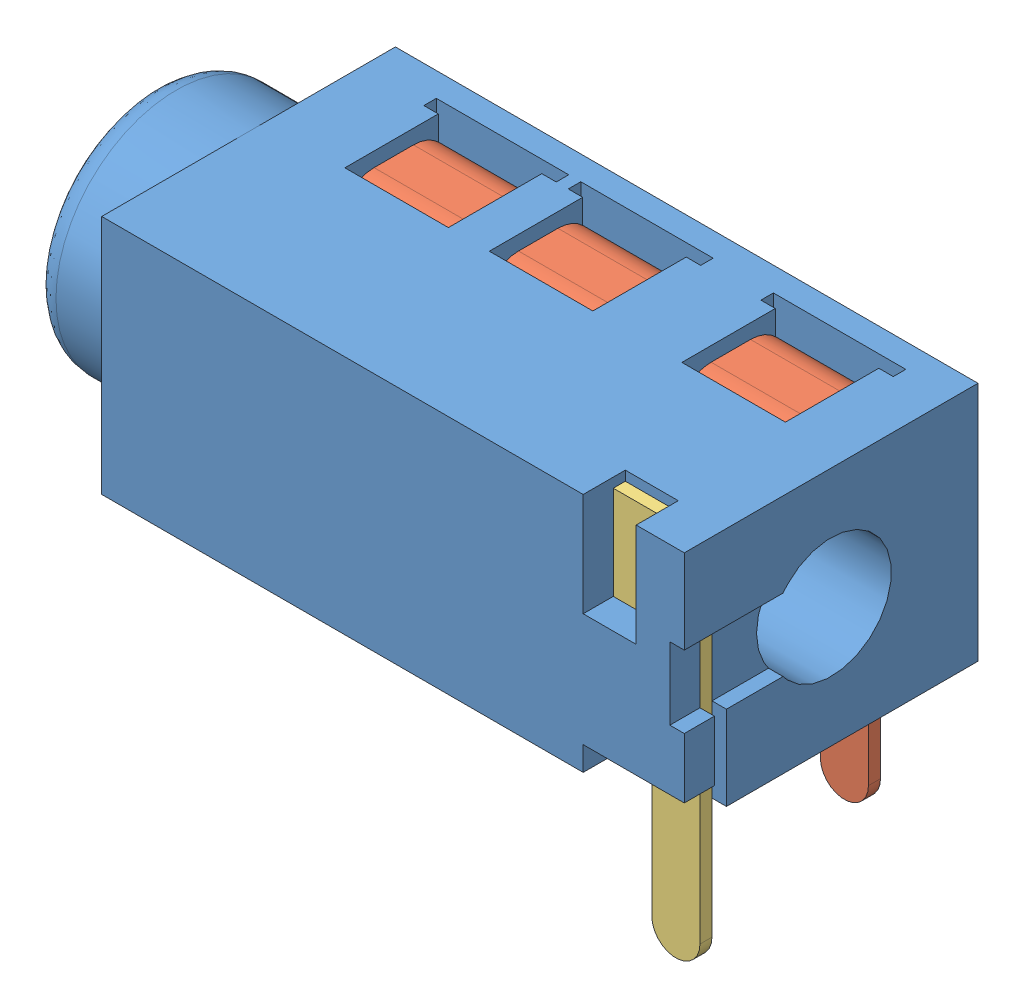
SolidWorks assembly PJ320A, configuration 默认. Lengths in mm.
Overall size (14.1 8 6.1).
5 component instances, 3 part files, 10 mates.
Components (placement in the parent):
- PJ320A胶壳-1: PJ320A胶壳 [默认] at (2.4399 13.6973 7.311) size (14.1 6 6.1)
- PJ320A-Pin-A-1: PJ320A-Pin-A [默认] at (6.1399 11.6833 5.136) x (0 1 0) z (0 0 1) size (7.8 1.95 2.32)
- PJ320A-Pin-B-1: PJ320A-Pin-B [默认] at (14.2399 13.6973 9.736) x (0 1 0) z (0 0 1) size (7.8 1.8 0.25)
- PJ320A-Pin-A-2: PJ320A-Pin-A [默认] at (9.1399 11.6833 5.136) x (0 1 0) z (0 0 1) size (7.8 1.95 2.32)
- PJ320A-Pin-A-3: PJ320A-Pin-A [默认] at (13.1399 11.6833 5.136) x (0 1 0) z (0 0 1) size (7.8 1.95 2.32)
Mates (geometry in assembly coordinates):
- 平行1: parallel aligned: plane of PJ320A胶壳-1 through (2.4399 18.6973 10.361) normal (-1 0 0); plane of PJ320A-Pin-A-1 through (4.1899 11.6833 5.136) normal (-1 0 0)
- 平行2: parallel aligned: plane of PJ320A胶壳-1 through (14.5399 18.6973 4.261) normal (0 0 -1); plane of PJ320A-Pin-A-1 through (5.6399 11.1973 4.886) normal (0 0 -1)
- 平行3: parallel anti-aligned: plane of PJ320A胶壳-1 through (14.5399 18.6973 10.361) normal (0 0 1); plane of PJ320A-Pin-B-1 through (14.2399 13.6973 9.486) normal (0 0 -1)
- 平行4: parallel aligned: plane of PJ320A胶壳-1 through (2.4399 18.6973 10.361) normal (-1 0 0); plane of PJ320A-Pin-B-1 through (12.4399 13.6973 9.486) normal (-1 0 0)
- 距离1: distance = 0.75 mm: moEndPointRef_w of PJ320A-Pin-A-1; plane of PJ320A胶壳-1 through (14.5399 18.6973 4.261) normal (0 0 -1)
- 距离2: distance = 3.2 mm: moEndPointRef_w of PJ320A-Pin-A-1; plane of PJ320A胶壳-1 through (2.4399 18.6973 10.361) normal (-1 0 0)
- 距离3: distance = 3 mm: moEndPointRef_w of PJ320A-Pin-A-1; plane of PJ320A胶壳-1 through (2.4399 13.6973 7.311) normal (0 -1 0)
- 距离4: distance = 0.75 mm: moEndPointRef_w of PJ320A-Pin-B-1; plane of PJ320A胶壳-1 through (14.5399 18.6973 10.361) normal (0 0 1)
- 距离5: distance = 11.3 mm: moEndPointRef_w of PJ320A-Pin-B-1; plane of PJ320A胶壳-1 through (2.4399 18.6973 10.361) normal (-1 0 0)
- 距离6: distance = 3 mm: moEndPointRef_w of PJ320A-Pin-B-1; plane of PJ320A胶壳-1 through (2.4399 13.6973 7.311) normal (0 -1 0)
